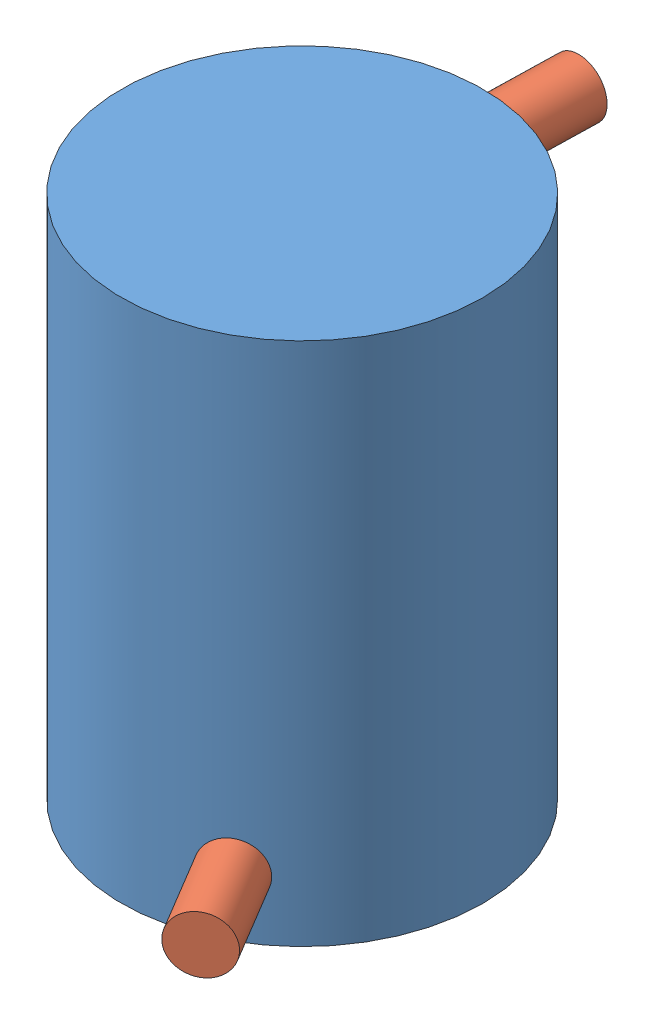
SolidWorks assembly Mouse House, configuration Default. Lengths in mm.
Overall size (70 101.6 101.95).
3 component instances, 2 part files, 2 mates.
Components (placement in the parent):
- Mouse_House-1: Mouse_House [Default] at (40.3909 20.1611 99.0093) size (70 101.6 70)
- Mouse House Holder Prong-1: Mouse House Holder Prong [Default] at (41.076 113.3684 46.0108) x (0.999722 0 0.023571) z (0 -1 0) size (11 18 11)
- Mouse House Holder Prong-2: Mouse House Holder Prong [Default] at (57.4962 31.9069 129.5604) x (0.858559 0 -0.512714) z (0 -1 0) size (11 18 11)
Mates (geometry in assembly coordinates):
- Tangent1: tangent anti-aligned: cylinder of Mouse_House-1 through (40.3909 -11.8589 99.0093) axis (0 -1 0) radius 35; plane of Mouse House Holder Prong-1 through (40.6517 113.3684 64.0058) normal (-0.023571 0 0.999722)
- Tangent3: tangent anti-aligned: cylinder of Mouse_House-1 through (40.3909 -11.8589 99.0093) axis (0 -1 0) radius 35; plane of Mouse House Holder Prong-2 through (57.4962 31.9069 129.5604) normal (-0.512714 0 -0.858559)
